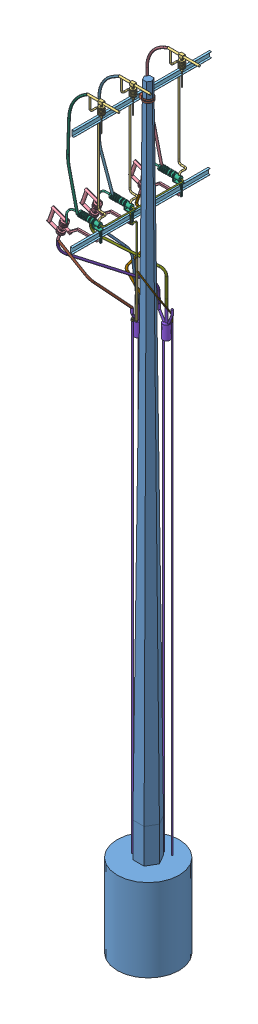
SolidWorks assembly LINEA AERÉA 13.2 KV POSTE No. 9, configuration Predeterminado. Lengths in mm.
Overall size (1312.95 11313.14 2000).
32 component instances, 21 part files, 17 mates.
Components (placement in the parent):
- SITEMA DE CABLEADO PARA BAJADA-1: SITEMA DE CABLEADO PARA BAJADA [Predeterminado] at (2886.5225 -253.8021 579.5549) size (1338.71 11313.14 2000)
  - POSTE DE SUBESTACIÓN-1: POSTE DE SUBESTACIÓN [Predeterminado] at (-6270.6938 -6573.1724 11000) size (900 11000 900)
  - FLEXX-1: FLEXX [Predeterminado] at (-6270.6938 4161.8552 11000) x (-1 0 0) z (0 0 -1) size (154.11 50 136.21)
  - CONECTADOR SUPERIOR-1: CONECTADOR SUPERIOR [Predeterminado] at (-6365.6938 4181.216 10415) x (0 0 1) z (-1 0 0) size (176.67 1669.06 455)
  - CORTO CIRCUITO FUSIBLE-1: CORTO CIRCUITO FUSIBLE [Predeterminado] at (-6907.9992 2496.6628 11635.8855) x (0 0 -1) z (0.943722 -0.330738 0) size (100 458.14 653.95)
  - CORTO CIRCUITO FUSIBLE-2: CORTO CIRCUITO FUSIBLE [Predeterminado] at (-6892.3975 2496.6628 10460.112) x (0 0 -1) z (0.943722 -0.330738 0) size (100 458.14 653.95)
  - CORTO CIRCUITO FUSIBLE-3: CORTO CIRCUITO FUSIBLE [Predeterminado] at (-6892.3975 2496.6628 11170.112) x (0 0 -1) z (0.943722 -0.330738 0) size (100 458.14 653.95)
  - CRUCETA-1: CRUCETA [Predeterminado] at (-6380.6938 4146.8276 9250) size (54 80 2000)
  - CRUCETA-2: CRUCETA [Predeterminado] at (-6400.6938 2666.8276 9250) size (54 80 2000)
  - ELEMENTO ELEC.-1: ELEMENTO ELEC. [Predeterminado] at (-6688.5888 2810.6406 11576.0986) x (0 0 1) z (0 1 0) size (120.76 447.39 257.81)
  - ELEMENTO ELEC.-2: ELEMENTO ELEC. [Predeterminado] at (-6688.5888 2810.6406 11116.0986) x (0 0 1) z (0 1 0) size (120.76 447.39 257.81)
  - ELEMENTO ELEC.-3: ELEMENTO ELEC. [Predeterminado] at (-6688.5888 2810.6406 10406.0986) x (0 0 1) z (0 1 0) size (120.76 447.39 257.81)
  - Pieza1^SITEMA DE CABLEADO PARA BAJADA-1: Pieza1^SITEMA DE CABLEADO PARA BAJADA [Predeterminado] at (-6698.5888 2810.6406 10406.0986) x (0 0 -1) z (-1 0 0) (virtual)
  - Conexión para rayos-1: Conexión para rayos [Predeterminado] at (-6388.5888 2810.6406 11576.0986) x (0 -0.002991 -0.999996) z (1 0 0) size (1185 1374.43 77.17)
  - CONECTADOR SUPERIOR-4: CONECTADOR SUPERIOR [Predeterminado] at (-6365.6938 4181.216 11125) x (0 0 1) z (-1 0 0) size (176.67 1669.06 455)
  - CONECTADOR SUPERIOR-5: CONECTADOR SUPERIOR [Predeterminado] at (-6365.6938 4181.216 11585) x (0 0 1) z (-1 0 0) size (176.67 1669.06 455)
  - Ensamblaje Bajada 4in-1: Ensamblaje Bajada 4in [Predeterminado] at (-5478.9855 4273.2276 7314.2555) x (0 0 -1) z (0 -1 0) size (208.6 120.54 8411) (hidden)
    - Manga para 3 fases-1: Manga para 3 fases [Predeterminado] at (-3685.7445 -940.5199 3148.5365) x (0.995258 -0.097274 0) z (0.097274 0.995258 0) size (199.67 8411 101.6)
  - Pieza4^SITEMA DE CABLEADO PARA BAJADA-1: Pieza4^SITEMA DE CABLEADO PARA BAJADA [Predeterminado] at (-6933.7398 2378.6975 10460.112) x (0 0 1) z (-0.330738 -0.943722 0) size (476.3 775.26 643.22) (hidden, virtual)
  - Pieza5^SITEMA DE CABLEADO PARA BAJADA-1: Pieza5^SITEMA DE CABLEADO PARA BAJADA [Predeterminado] at (-6419.5055 1524.691 11000) x (-0.097274 0 -0.995258) z (0 1 0) size (201.42 550.24 868.68) (hidden, virtual)
  - Pieza6^SITEMA DE CABLEADO PARA BAJADA-1: Pieza6^SITEMA DE CABLEADO PARA BAJADA [Predeterminado] at (-6419.5055 1524.691 11000) x (-0.097274 0 -0.995258) z (0 1 0) size (508.8 611.2 872.94) (hidden, virtual)
  - Pieza7^SITEMA DE CABLEADO PARA BAJADA-1: Pieza7^SITEMA DE CABLEADO PARA BAJADA [Predeterminado] at (-6419.5055 1324.691 11000) x (-0.097274 0 -0.995258) z (0 1 0) size (94.9 136.25 118.4) (hidden, virtual)
  - Pieza3^SITEMA DE CABLEADO PARA BAJADA-1: Pieza3^SITEMA DE CABLEADO PARA BAJADA [Predeterminado] at (-6395.6938 4181.216 10415) x (0 0 1) z (-1 0 0) size (78.57 1581.62 325.05) (virtual)
  - Pieza8^SITEMA DE CABLEADO PARA BAJADA-1: Pieza8^SITEMA DE CABLEADO PARA BAJADA [Predeterminado] at (-6565.6938 4181.216 11125) x (0 0 1) z (-1 0 0) size (29.07 1561.95 311.16) (virtual)
  - Pieza9^SITEMA DE CABLEADO PARA BAJADA-1: Pieza9^SITEMA DE CABLEADO PARA BAJADA [Predeterminado] at (-6565.6938 4181.216 11585) x (0 0 1) z (-1 0 0) size (55.93 1568.55 310.09) (virtual)
- Ensamblaje Bajada 4in-1: Ensamblaje Bajada 4in [Predeterminado] at (401.5732 4021.4935 12354.8104) x (1 0 0) z (0 -1 0) size (208.6 120.54 8411)
  - Manga para 3 fases-1: Manga para 3 fases [Predeterminado] at (-3685.7445 -940.5199 3148.5365) x (0.995258 -0.097274 0) z (0.097274 0.995258 0) size (199.67 8411 101.6)
- Pieza1^LINEA AERÉA 13.2 KV POSTE No. 9-1: Pieza1^LINEA AERÉA 13.2 KV POSTE No. 9 [Predeterminado] at origin (virtual)
- Pieza2^LINEA AERÉA 13.2 KV POSTE No. 9-1: Pieza2^LINEA AERÉA 13.2 KV POSTE No. 9 [Predeterminado] at (-3284.1713 1272.9569 11414.2905) x (0.995258 0 -0.097274) z (0 1 0) (virtual)
- Pieza4^LINEA AERÉA 13.2 KV POSTE No. 9-1: Pieza4^LINEA AERÉA 13.2 KV POSTE No. 9 [Predeterminado] at (-3284.1713 1272.9569 11414.2905) x (0.995258 0 -0.097274) z (0 1 0) size (819.45 286.96 851.94) (virtual)
- Pieza5^LINEA AERÉA 13.2 KV POSTE No. 9-1: Pieza5^LINEA AERÉA 13.2 KV POSTE No. 9 [Predeterminado] at (-3284.1713 1272.9569 11414.2905) x (0.995258 0 -0.097274) z (0 1 0) size (783.11 749.29 852.72) (virtual)
- Pieza6^LINEA AERÉA 13.2 KV POSTE No. 9-1: Pieza6^LINEA AERÉA 13.2 KV POSTE No. 9 [Predeterminado] at (-3284.1713 1082.9569 11414.2905) x (0.995258 0 -0.097274) z (0 1 0) size (251.38 312.24 727.11) (virtual)
Mates (geometry in assembly coordinates):
- Distancia2: distance = 100 mm aligned: plane of SITEMA DE CABLEADO PARA BAJADA-1/POSTE DE SUBESTACIÓN-1 through (-3384.1713 -6826.9746 11579.5549) normal (1 0 0); plane of ? through (-3284.1713 995.0935 11414.2905) normal (1 0 0)
- EnPosición1: in place: plane of Ensamblaje Bajada 4in-1/Manga para 3 fases-1 through (-3284.1713 1272.9569 11414.2905) normal (0 1 0); plane of ? through (0 1272.9569 0) normal (0 1 0); moOrthogonalPlaneRef_w of Ensamblaje Bajada 4in-1/Manga para 3 fases-1 through (-3284.1713 1272.9569 11414.2905) normal (0 1 0); plane of ? through (0 1272.9569 0) normal (0 0 -1); plane of Ensamblaje Bajada 4in-1/Manga para 3 fases-1 through (-3284.1713 1272.9569 11414.2905) normal (0 1 0); unknown of ?; plane of Ensamblaje Bajada 4in-1/Manga para 3 fases-1 through (-3284.1713 1272.9569 11414.2905) normal (0 1 0); unknown of ?
- Coincidente4: coincident aligned: plane of Ensamblaje Bajada 4in-1/Manga para 3 fases-1; plane of Pieza2^LINEA AERÉA 13.2 KV POSTE No. 9-1
- Coincidente5: coincident aligned: moOrthogonalPlaneRef_w of Ensamblaje Bajada 4in-1/Manga para 3 fases-1 through (-3284.1713 1272.9569 11414.2905) normal (-0.097274 0 -0.995258); plane of Pieza2^LINEA AERÉA 13.2 KV POSTE No. 9-1
- Coincidente6: coincident anti-aligned: moOrthogonalPlaneRef_w of Ensamblaje Bajada 4in-1/Manga para 3 fases-1 through (-3284.1713 1272.9569 11414.2905) normal (-0.995258 0 0.097274); plane of Pieza2^LINEA AERÉA 13.2 KV POSTE No. 9-1
- EnPosición3: in place: plane of Ensamblaje Bajada 4in-1/Manga para 3 fases-1 through (-3284.1713 1272.9569 11414.2905) normal (0 1 0); plane of ? through (0 1272.9569 0) normal (0 1 0); plane of Ensamblaje Bajada 4in-1/Manga para 3 fases-1 through (-3284.1713 1272.9569 11414.2905) normal (0 1 0); plane of ? through (0 1272.9569 0) normal (0 0 -1); plane of Ensamblaje Bajada 4in-1/Manga para 3 fases-1 through (-3284.1713 1272.9569 11414.2905) normal (0 1 0); unknown of ?; plane of Ensamblaje Bajada 4in-1/Manga para 3 fases-1 through (-3284.1713 1272.9569 11414.2905) normal (0 1 0); unknown of ?
- Coincidente10: coincident aligned: plane of Ensamblaje Bajada 4in-1/Manga para 3 fases-1; plane of Pieza4^LINEA AERÉA 13.2 KV POSTE No. 9-1
- Coincidente11: coincident aligned: moOrthogonalPlaneRef_w of Ensamblaje Bajada 4in-1/Manga para 3 fases-1 through (-3284.1713 1272.9569 11414.2905) normal (-0.097274 0 -0.995258); plane of Pieza4^LINEA AERÉA 13.2 KV POSTE No. 9-1
- Coincidente12: coincident anti-aligned: moOrthogonalPlaneRef_w of Ensamblaje Bajada 4in-1/Manga para 3 fases-1 through (-3284.1713 1272.9569 11414.2905) normal (-0.995258 0 0.097274); plane of Pieza4^LINEA AERÉA 13.2 KV POSTE No. 9-1
- EnPosición4: in place: plane of Ensamblaje Bajada 4in-1/Manga para 3 fases-1 through (-3284.1713 1272.9569 11414.2905) normal (0 1 0); plane of ? through (0 1272.9569 0) normal (0 1 0); plane of Ensamblaje Bajada 4in-1/Manga para 3 fases-1 through (-3284.1713 1272.9569 11414.2905) normal (0 1 0); plane of ? through (0 1272.9569 0) normal (0 0 -1); plane of Ensamblaje Bajada 4in-1/Manga para 3 fases-1 through (-3284.1713 1272.9569 11414.2905) normal (0 1 0); unknown of ?; plane of Ensamblaje Bajada 4in-1/Manga para 3 fases-1 through (-3284.1713 1272.9569 11414.2905) normal (0 1 0); unknown of ?
- Coincidente13: coincident aligned: plane of Ensamblaje Bajada 4in-1/Manga para 3 fases-1; plane of Pieza5^LINEA AERÉA 13.2 KV POSTE No. 9-1
- Coincidente14: coincident aligned: moOrthogonalPlaneRef_w of Ensamblaje Bajada 4in-1/Manga para 3 fases-1 through (-3284.1713 1272.9569 11414.2905) normal (-0.097274 0 -0.995258); plane of Pieza5^LINEA AERÉA 13.2 KV POSTE No. 9-1
- Coincidente15: coincident anti-aligned: moOrthogonalPlaneRef_w of Ensamblaje Bajada 4in-1/Manga para 3 fases-1 through (-3284.1713 1272.9569 11414.2905) normal (-0.995258 0 0.097274); plane of Pieza5^LINEA AERÉA 13.2 KV POSTE No. 9-1
- EnPosición5: in place: plane of Ensamblaje Bajada 4in-1/Manga para 3 fases-1 through (-3236.5341 1082.9569 11379.4537) normal (0 1 0); plane of ? through (0 1082.9569 0) normal (0 1 0); plane of Ensamblaje Bajada 4in-1/Manga para 3 fases-1 through (-3236.5341 1082.9569 11379.4537) normal (0 1 0); plane of ? through (0 1082.9569 0) normal (0 0 -1); plane of Ensamblaje Bajada 4in-1/Manga para 3 fases-1 through (-3236.5341 1082.9569 11379.4537) normal (0 1 0); unknown of ?; plane of Ensamblaje Bajada 4in-1/Manga para 3 fases-1 through (-3236.5341 1082.9569 11379.4537) normal (0 1 0); unknown of Pieza6^LINEA AERÉA 13.2 KV POSTE No. 9-1
- Coincidente16: coincident aligned: plane of Ensamblaje Bajada 4in-1/Manga para 3 fases-1; plane of Pieza6^LINEA AERÉA 13.2 KV POSTE No. 9-1
- Coincidente17: coincident aligned: moOrthogonalPlaneRef_w of Ensamblaje Bajada 4in-1/Manga para 3 fases-1 through (-3284.1713 1082.9569 11414.2905) normal (-0.097274 0 -0.995258); plane of Pieza6^LINEA AERÉA 13.2 KV POSTE No. 9-1
- Coincidente18: coincident anti-aligned: moOrthogonalPlaneRef_w of Ensamblaje Bajada 4in-1/Manga para 3 fases-1 through (-3284.1713 1082.9569 11414.2905) normal (-0.995258 0 0.097274); plane of Pieza6^LINEA AERÉA 13.2 KV POSTE No. 9-1
